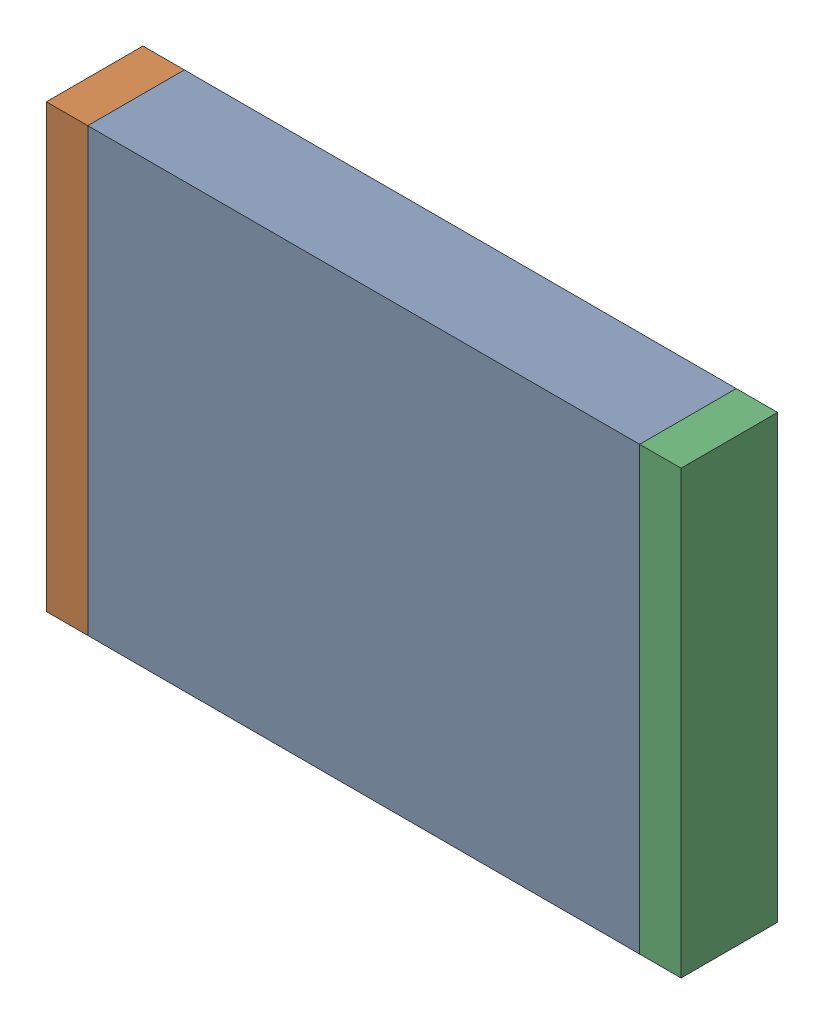
SolidWorks assembly F1, configuration Default. Lengths in mm.
Overall size (4.6 3.2 0.7).
6 component instances, 2 part files, 0 mates.
Components (placement in the parent):
- 870945440-1: 870945440 [Default] at (78.613 32.258 -2.3006) size (4 3.2 0.7)
  - Extruded_28-1: Extruded_28 [Default] at origin size (4 3.2 0.7)
- 870945600-1: 870945600 [Default] at (76.463 32.258 -2.3006) size (0.3 3.2 0.7)
  - Extruded_29-1: Extruded_29 [Default] at origin size (0.3 3.2 0.7)
- 870945600-2: 870945600 [Default] at (80.763 32.258 -2.3006) size (0.3 3.2 0.7)
  - Extruded_29-1: Extruded_29 [Default] at origin size (0.3 3.2 0.7)
